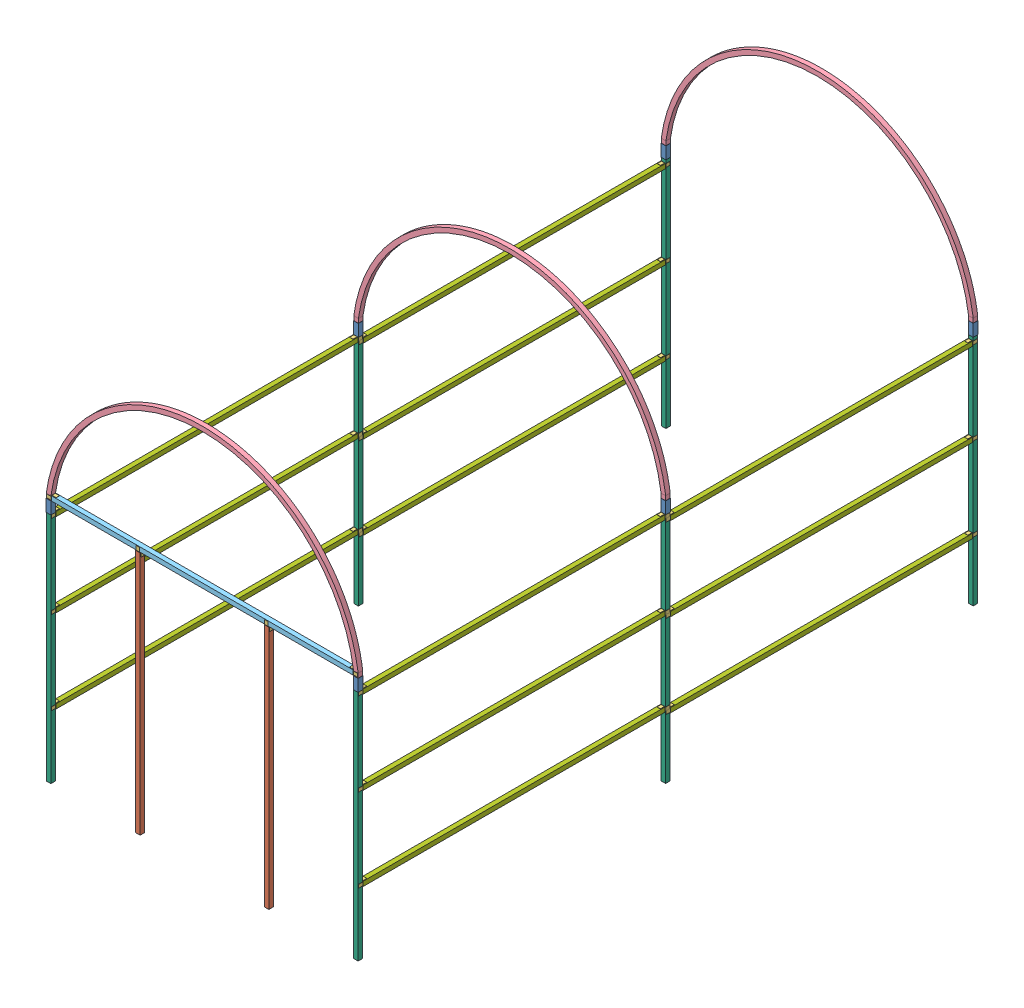
SolidWorks assembly SolarDryer_Frame, configuration Default. Lengths in mm.
Overall size (2062 2546.04 4095).
87 component instances, 8 part files, 49 mates.
Components (placement in the parent):
- Vertical joint-1: Vertical joint [Default] at (-1015 770.5 -2160.8996) size (32 80 32)
- VerticalBar-1: VerticalBar [Default] at (-425 0 -2160.8996) x (-1 0 0) z (0 0 1) size (30 1615 30)
- Wrapper-1: Wrapper [Default] at (-425 780.5 -2160.8996) x (0 0 -1) z (0 1 0) size (22 32 30)
- Arc_Bar-1: Arc_Bar [Default] at (0 838.5301 -2160.8996) x (0 0 -1) z (1 0 0) size (30.03 960.01 2060)
- LateralBar-1: LateralBar [Default] at (0 826.5 -2160.8996) x (0 0 -1) z (1 0 0) size (30 30 1992)
- Back_Wall-1: Back_Wall [Default] at (0 800 -2178.3996) size (2060 2500 5) (hidden)
- Wrapper-4: Wrapper [Default] at (-1027 826.5 -2160.8996) x (0 1 0) z (1 0 0) size (22 32 30)
- Wrapper-5: Wrapper [Default] at (-969 826.5 -2160.8996) x (0 0 1) z (-1 0 0) size (22 32 30)
- VerticalBar_Corners-1: VerticalBar_Corners [Default] at (-1015 -14.4849 -2160.8996) size (30 1586.03 30)
- Wrapper-8: Wrapper [Default] at (-425 838.5 -2160.8996) x (1 0 0) z (0 -1 0) size (22 32 30)
- VerticalBar-2: VerticalBar [Default] at (425 0 -2160.8996) x (1 0 0) z (0 0 -1) size (30 1615 30)
- Wrapper-9: Wrapper [Default] at (425 838.5 -2160.8996) x (1 0 0) z (0 -1 0) size (22 32 30)
- Wrapper-10: Wrapper [Default] at (425 780.5 -2160.8996) x (0 0 1) z (0 1 0) size (22 32 30)
- VerticalBar_Corners-2: VerticalBar_Corners [Default] at (1015 -14.4849 -2160.8996) x (-1 0 0) z (0 0 -1) size (30 1586.03 30)
- Vertical joint-2: Vertical joint [Default] at (1015 770.5 -2160.8996) x (-1 0 0) z (0 0 -1) size (32 80 32)
- Wrapper-11: Wrapper [Default] at (1027 826.5 -2160.8996) x (0 -1 0) z (-1 0 0) size (22 32 30)
- Wrapper-12: Wrapper [Default] at (969 826.5 -2160.8996) x (0 0 -1) z (1 0 0) size (22 32 30)
- VerticalBar_Corners-7: VerticalBar_Corners [Default] at (-1015 -14.4849 -4192.3996) size (30 1586.03 30)
- VerticalBar_Corners-8: VerticalBar_Corners [Default] at (-1015 -14.4849 -6223.8996) size (30 1586.03 30)
- Vertical joint-7: Vertical joint [Default] at (-1015 770.5 -4192.3996) size (32 80 32)
- Vertical joint-8: Vertical joint [Default] at (-1015 770.5 -6223.8996) size (32 80 32)
- VerticalBar_Corners-9: VerticalBar_Corners [Default] at (1015 -14.4849 -4192.3996) x (-1 0 0) z (0 0 -1) size (30 1586.03 30)
- VerticalBar_Corners-10: VerticalBar_Corners [Default] at (1015 -14.4849 -6223.8996) x (-1 0 0) z (0 0 -1) size (30 1586.03 30)
- Vertical joint-9: Vertical joint [Default] at (1015 770.5 -4192.3996) x (-1 0 0) z (0 0 -1) size (32 80 32)
- Vertical joint-10: Vertical joint [Default] at (1015 770.5 -6223.8996) x (-1 0 0) z (0 0 -1) size (32 80 32)
- Arc_Bar-4: Arc_Bar [Default] at (0 838.5301 -4192.3996) x (0 0 -1) z (1 0 0) size (30.03 960.01 2060)
- Arc_Bar-5: Arc_Bar [Default] at (0 838.5301 -6223.8996) x (0 0 -1) z (1 0 0) size (30.03 960.01 2060)
- Wrapper-13: Wrapper [Default] at (1015 719.5 -2148.8996) x (0 1 0) z (0 0 -1) size (22 32 30)
- Wrapper-15: Wrapper [Default] at (1015 717.5 -2206.8996) size (22 32 30)
- Wrapper-16: Wrapper [Default] at (1015 719.5 -4204.3996) x (0 -1 0) z (0 0 1) size (22 32 30)
- Wrapper-17: Wrapper [Default] at (1015 717.5 -4146.3996) x (-1 0 0) z (0 0 -1) size (22 32 30)
- HorizontalBarSides-1: HorizontalBarSides [Default] at (1015 717.5 -4174.3996) size (30 30 1995.5)
- Wrapper-22: Wrapper [Default] at (1015 697.5 -4180.3996) x (0 1 0) z (0 0 -1) size (22 32 30)
- Wrapper-23: Wrapper [Default] at (1015 695.5 -4238.3996) size (22 32 30)
- HorizontalBarSides-3: HorizontalBarSides [Default] at (1015 695.5 -6205.8996) size (30 30 1995.5)
- Wrapper-24: Wrapper [Default] at (1015 697.5 -6235.8996) x (0 -1 0) z (0 0 1) size (22 32 30)
- Wrapper-25: Wrapper [Default] at (1015 695.5 -6177.8996) x (-1 0 0) z (0 0 -1) size (22 32 30)
- Wrapper-26: Wrapper [Default] at (1015 147.5 -6235.8996) x (0 -1 0) z (0 0 1) size (22 32 30)
- Wrapper-27: Wrapper [Default] at (1015 -402.5 -6235.8996) x (0 -1 0) z (0 0 1) size (22 32 30)
- Wrapper-28: Wrapper [Default] at (1015 145.5 -6177.8996) x (-1 0 0) z (0 0 -1) size (22 32 30)
- Wrapper-29: Wrapper [Default] at (1015 -404.5 -6177.8996) x (-1 0 0) z (0 0 -1) size (22 32 30)
- HorizontalBarSides-4: HorizontalBarSides [Default] at (1015 145.5 -6205.8996) size (30 30 1995.5)
- HorizontalBarSides-5: HorizontalBarSides [Default] at (1015 -404.5 -6205.8996) size (30 30 1995.5)
- Wrapper-30: Wrapper [Default] at (1015 145.5 -4238.3996) size (22 32 30)
- Wrapper-31: Wrapper [Default] at (1015 -404.5 -4238.3996) size (22 32 30)
- Wrapper-32: Wrapper [Default] at (1015 147.5 -4180.3996) x (0 1 0) z (0 0 -1) size (22 32 30)
- Wrapper-33: Wrapper [Default] at (1015 -402.5 -4180.3996) x (0 1 0) z (0 0 -1) size (22 32 30)
- Wrapper-34: Wrapper [Default] at (1015 169.5 -4204.3996) x (0 -1 0) z (0 0 1) size (22 32 30)
- Wrapper-35: Wrapper [Default] at (1015 -380.5 -4204.3996) x (0 -1 0) z (0 0 1) size (22 32 30)
- Wrapper-36: Wrapper [Default] at (1015 167.5 -4146.3996) x (-1 0 0) z (0 0 -1) size (22 32 30)
- Wrapper-37: Wrapper [Default] at (1015 -382.5 -4146.3996) x (-1 0 0) z (0 0 -1) size (22 32 30)
- HorizontalBarSides-6: HorizontalBarSides [Default] at (1015 167.5 -4174.3996) size (30 30 1995.5)
- HorizontalBarSides-7: HorizontalBarSides [Default] at (1015 -382.5 -4174.3996) size (30 30 1995.5)
- Wrapper-38: Wrapper [Default] at (1015 169.5 -2148.8996) x (0 1 0) z (0 0 -1) size (22 32 30)
- Wrapper-39: Wrapper [Default] at (1015 -380.5 -2148.8996) x (0 1 0) z (0 0 -1) size (22 32 30)
- Wrapper-40: Wrapper [Default] at (1015 167.5 -2206.8996) size (22 32 30)
- Wrapper-41: Wrapper [Default] at (1015 -382.5 -2206.8996) size (22 32 30)
- Wrapper-42: Wrapper [Default] at (-1015 697.5 -6235.8996) x (0 1 0) z (0 0 1) size (22 32 30)
- Wrapper-43: Wrapper [Default] at (-1015 695.5 -6177.8996) x (-1 0 0) z (0 0 -1) size (22 32 30)
- HorizontalBarSides-8: HorizontalBarSides [Default] at (-1015 695.5 -4210.3996) x (-1 0 0) z (0 0 -1) size (30 30 1995.5)
- Wrapper-44: Wrapper [Default] at (-1015 695.5 -4238.3996) size (22 32 30)
- Wrapper-45: Wrapper [Default] at (-1015 697.5 -4180.3996) x (0 -1 0) z (0 0 -1) size (22 32 30)
- Wrapper-46: Wrapper [Default] at (-1015 719.5 -4204.3996) x (0 1 0) z (0 0 1) size (22 32 30)
- Wrapper-47: Wrapper [Default] at (-1015 717.5 -4146.3996) x (-1 0 0) z (0 0 -1) size (22 32 30)
- HorizontalBarSides-9: HorizontalBarSides [Default] at (-1015 717.5 -2178.8996) x (-1 0 0) z (0 0 -1) size (30 30 1995.5)
- Wrapper-48: Wrapper [Default] at (-1015 719.5 -2148.8996) x (0 -1 0) z (0 0 -1) size (22 32 30)
- Wrapper-49: Wrapper [Default] at (-1015 717.5 -2206.8996) size (22 32 30)
- Wrapper-50: Wrapper [Default] at (-1015 147.5 -6235.8996) x (0 1 0) z (0 0 1) size (22 32 30)
- Wrapper-51: Wrapper [Default] at (-1015 -402.5 -6235.8996) x (0 1 0) z (0 0 1) size (22 32 30)
- Wrapper-52: Wrapper [Default] at (-1015 145.5 -6177.8996) x (-1 0 0) z (0 0 -1) size (22 32 30)
- Wrapper-53: Wrapper [Default] at (-1015 -404.5 -6177.8996) x (-1 0 0) z (0 0 -1) size (22 32 30)
- HorizontalBarSides-10: HorizontalBarSides [Default] at (-1015 145.5 -4210.3996) x (-1 0 0) z (0 0 -1) size (30 30 1995.5)
- HorizontalBarSides-11: HorizontalBarSides [Default] at (-1015 -404.5 -4210.3996) x (-1 0 0) z (0 0 -1) size (30 30 1995.5)
- Wrapper-54: Wrapper [Default] at (-1015 145.5 -4238.3996) size (22 32 30)
- Wrapper-55: Wrapper [Default] at (-1015 -404.5 -4238.3996) size (22 32 30)
- Wrapper-56: Wrapper [Default] at (-1015 147.5 -4180.3996) x (0 -1 0) z (0 0 -1) size (22 32 30)
- Wrapper-57: Wrapper [Default] at (-1015 -402.5 -4180.3996) x (0 -1 0) z (0 0 -1) size (22 32 30)
- Wrapper-58: Wrapper [Default] at (-1015 169.5 -4204.3996) x (0 1 0) z (0 0 1) size (22 32 30)
- Wrapper-59: Wrapper [Default] at (-1015 -380.5 -4204.3996) x (0 1 0) z (0 0 1) size (22 32 30)
- Wrapper-60: Wrapper [Default] at (-1015 167.5 -4146.3996) x (-1 0 0) z (0 0 -1) size (22 32 30)
- Wrapper-61: Wrapper [Default] at (-1015 -382.5 -4146.3996) x (-1 0 0) z (0 0 -1) size (22 32 30)
- HorizontalBarSides-12: HorizontalBarSides [Default] at (-1015 167.5 -2178.8996) x (-1 0 0) z (0 0 -1) size (30 30 1995.5)
- HorizontalBarSides-13: HorizontalBarSides [Default] at (-1015 -382.5 -2178.8996) x (-1 0 0) z (0 0 -1) size (30 30 1995.5)
- Wrapper-62: Wrapper [Default] at (-1015 169.5 -2148.8996) x (0 -1 0) z (0 0 -1) size (22 32 30)
- Wrapper-63: Wrapper [Default] at (-1015 -380.5 -2148.8996) x (0 -1 0) z (0 0 -1) size (22 32 30)
- Wrapper-64: Wrapper [Default] at (-1015 167.5 -2206.8996) size (22 32 30)
- Wrapper-65: Wrapper [Default] at (-1015 -382.5 -2206.8996) size (22 32 30)
Mates (geometry in assembly coordinates):
- Coincident1: coincident anti-aligned: plane of Back_Wall-1 through (1030 0 -2175.8996) normal (0 -1 0)
- Coincident6: coincident anti-aligned: plane of LateralBar-1 through (996 811.5 -2175.8996) normal (0 0 -1); plane of Back_Wall-1 through (0 1460.6111 -2175.8996) normal (0 0 1)
- Coincident12: coincident aligned: plane of Back_Wall-1 through (0 800 -2178.3996) normal (1 0 0)
- Coincident15: coincident anti-aligned: plane of LateralBar-1 through (996 841.5 -2145.8996) normal (0 1 0); plane of Wrapper-5 through (-996 841.5 -2171.8996) normal (0 -1 0)
- Coincident16: coincident anti-aligned: plane of LateralBar-1 through (996 811.5 -2145.8996) normal (0 -1 0); plane of Wrapper-5 through (-969 811.5 -2171.8996) normal (0 1 0)
- Parallel4: parallel aligned: plane of LateralBar-1 through (996 811.5 -2175.8996) normal (0 0 -1); plane of Wrapper-5 through (-996 842.5 -2171.8996) normal (0 0 -1)
- Coincident19: coincident anti-aligned: plane of LateralBar-1 through (0 826.5 -2160.8996) normal (0 0 -1); plane of Wrapper-5 through (-969 826.5 -2160.8996) normal (0 0 1)
- Coincident23: coincident anti-aligned: plane of Wrapper-4 through (-998 815.5 -2173.8996) normal (-1 0 0); plane of Wrapper-5 through (-998 813.5 -2171.8996) normal (1 0 0)
- Coincident25: coincident aligned: plane of Wrapper-4 through (-1027 826.5 -2160.8996) normal (0 1 0); plane of Wrapper-5 through (-969 826.5 -2160.8996) normal (0 1 0)
- Coincident26: coincident aligned: plane of Arc_Bar-1; plane of LateralBar-1 through (0 826.5 -2160.8996) normal (1 0 0)
- Coincident27: coincident aligned: plane of Arc_Bar-1; plane of LateralBar-1 through (0 826.5 -2160.8996) normal (1 0 0)
- Parallel5: parallel anti-aligned: line of Arc_Bar-1 through (-1000 837.5 -2145.8996) axis (0 0 -1); line of LateralBar-1 through (-996 841.5 -2175.8996) axis (0 0 1)
- Coincident31: coincident: point of Arc_Bar-1; point of Wrapper-4
- Coincident32: coincident anti-aligned: plane of Vertical joint-1 through (-1000 810.5 -2175.8996) normal (0 0 1); plane of Arc_Bar-1 through (0 778.5301 -2175.8996) normal (0 0 -1)
- Coincident33: coincident anti-aligned: plane of Vertical joint-1 through (-1030 810.5 -2175.8996) normal (1 0 0); plane of Arc_Bar-1 through (-1030 778.5301 -2160.8996) normal (-1 0 0)
- Coincident34: coincident anti-aligned: plane of Wrapper-4 through (-998 815.5 -2173.8996) normal (-1 0 0); plane of Wrapper-5 through (-998 813.5 -2171.8996) normal (1 0 0)
- Coincident35: coincident aligned: plane of Wrapper-4 through (-1027 826.5 -2160.8996) normal (0 0 1); plane of Wrapper-5 through (-969 826.5 -2160.8996) normal (0 0 1)
- Coincident36: coincident anti-aligned: plane of Vertical joint-1 through (-1015 810.5 -2160.8996) normal (0 1 0); plane of Wrapper-5 through (-969 810.5 -2171.8996) normal (0 -1 0)
- Coincident42: coincident anti-aligned: line of VerticalBar-1 through (-410 807.5 -2175.8996) axis (0 0 1); line of Wrapper-1 through (-410 807.5 -2149.8996) axis (0 0 -1)
- Coincident43: coincident aligned: line of VerticalBar-1 through (-440 807.5 -2145.8996) axis (0 0 -1); line of Wrapper-1 through (-440 807.5 -2149.8996) axis (0 0 -1)
- Coincident44: coincident anti-aligned: plane of VerticalBar-1 through (-425 0 -2160.8996) normal (0 0 1); plane of Wrapper-1 through (-425 780.5 -2160.8996) normal (0 0 -1)
- Coincident45: coincident anti-aligned: plane of VerticalBar-1 through (-425 0 -2160.8996) normal (0 0 1); plane of LateralBar-1 through (0 826.5 -2160.8996) normal (0 0 -1)
- Parallel6: parallel anti-aligned: plane of VerticalBar-1 through (-425 0 -2160.8996) normal (-1 0 0); plane of LateralBar-1 through (0 826.5 -2160.8996) normal (1 0 0)
- Distance3: distance = 425 mm anti-aligned: plane of VerticalBar-1 through (-425 0 -2160.8996) normal (-1 0 0); plane of LateralBar-1 through (0 826.5 -2160.8996) normal (1 0 0)
- Coincident48: coincident anti-aligned: plane of Wrapper-1 through (-412 809.5 -2149.8996) normal (0 -1 0); plane of Wrapper-8 through (-436 809.5 -2173.8996) normal (0 1 0)
- Coincident49: coincident anti-aligned: plane of Wrapper-1 through (-425 780.5 -2160.8996) normal (-1 0 0); plane of Wrapper-8 through (-425 838.5 -2160.8996) normal (1 0 0)
- Coincident50: coincident anti-aligned: plane of Wrapper-1 through (-425 780.5 -2160.8996) normal (0 0 -1); plane of Wrapper-8 through (-425 838.5 -2160.8996) normal (0 0 1)
- Coincident51: coincident anti-aligned: line of LateralBar-1 through (996 811.5 -2145.8996) axis (-1 0 0); line of Wrapper-8 through (-436 811.5 -2145.8996) axis (1 0 0)
- Coincident52: coincident anti-aligned: plane of Arc_Bar-1 through (0 778.5301 -2160.8996) normal (0 -1 0); plane of VerticalBar_Corners-1 through (-1015 778.5301 -2160.8996) normal (0 1 0)
- Coincident53: coincident anti-aligned: plane of Vertical joint-1 through (-1000 810.5 -2175.8996) normal (0 0 1); plane of VerticalBar_Corners-1 through (-1030 778.5301 -2175.8996) normal (0 0 -1)
- Coincident54: coincident anti-aligned: plane of Vertical joint-1 through (-1000 810.5 -2175.8996) normal (-1 0 0); plane of VerticalBar_Corners-1 through (-1000 778.5301 -2175.8996) normal (1 0 0)
- Coincident57: coincident anti-aligned: plane of VerticalBar-1 through (-425 0 -2160.8996) normal (0 -1 0)
- Coincident58: coincident anti-aligned: line of VerticalBar_Corners-2 through (1000 778.5301 -2175.8996) axis (0 -1 0); line of Wrapper-13 through (1000 708.5 -2175.8996) axis (0 1 0)
- Coincident59: coincident anti-aligned: line of VerticalBar_Corners-2 through (1030 778.5301 -2175.8996) axis (0 -1 0); line of Wrapper-13 through (1030 708.5 -2175.8996) axis (0 1 0)
- Coincident60: coincident aligned: plane of Wrapper-13 through (1015 719.5 -2148.8996) normal (1 0 0); plane of Wrapper-15 through (1015 717.5 -2206.8996) normal (1 0 0)
- Coincident61: coincident aligned: plane of Wrapper-13 through (1015 719.5 -2148.8996) normal (1 0 0); plane of Wrapper-15 through (1015 717.5 -2206.8996) normal (1 0 0)
- Coincident63: coincident anti-aligned: plane of Wrapper-13 through (1002 708.5 -2177.8996) normal (0 0 1); plane of Wrapper-15 through (1004 704.5 -2177.8996) normal (0 0 -1)
- Coincident64: coincident anti-aligned: plane of Vertical joint-2 through (1015 730.5 -2160.8996) normal (0 -1 0); plane of Wrapper-13 through (1031 730.5 -2175.8996) normal (0 1 0)
- Coincident65: coincident aligned: line of Wrapper-13 through (1002 730.5 -2177.8996) axis (1 0 0); line of Wrapper-15 through (1004 730.5 -2177.8996) axis (1 0 0)
- Coincident67: coincident aligned: line of VerticalBar_Corners-9 through (1000 778.5301 -4177.3996) axis (0 -1 0); line of Wrapper-16 through (1000 730.5 -4177.3996) axis (0 -1 0)
- Coincident68: coincident aligned: unknown of Arc_Bar-1
- Coincident69: coincident aligned: line of VerticalBar_Corners-9 through (1030 778.5301 -4177.3996) axis (0 -1 0); line of Wrapper-16 through (1030 730.5 -4177.3996) axis (0 -1 0)
- Coincident70: coincident anti-aligned: plane of Vertical joint-9 through (1015 730.5 -4192.3996) normal (0 -1 0); plane of Wrapper-16 through (1031 730.5 -4177.3996) normal (0 1 0)
- Coincident71: coincident anti-aligned: plane of Wrapper-16 through (1002 730.5 -4175.3996) normal (0 0 -1); plane of Wrapper-17 through (1026 704.5 -4175.3996) normal (0 0 1)
- Coincident72: coincident anti-aligned: line of Wrapper-16 through (1002 730.5 -4175.3996) axis (1 0 0); line of Wrapper-17 through (1026 730.5 -4175.3996) axis (-1 0 0)
- Coincident73: coincident anti-aligned: plane of Wrapper-16 through (1015 719.5 -4204.3996) normal (1 0 0); plane of Wrapper-17 through (1015 717.5 -4146.3996) normal (-1 0 0)
- Coincident74: coincident anti-aligned: plane of Wrapper-16 through (1002 730.5 -4174.3996) normal (0 0 1); plane of HorizontalBarSides-1 through (1015 717.5 -4174.3996) normal (0 0 -1)
- Coincident75: coincident anti-aligned: plane of Wrapper-17 through (1015 717.5 -4146.3996) normal (-1 0 0); plane of HorizontalBarSides-1 through (1015 717.5 -4174.3996) normal (1 0 0)
- Coincident76: coincident anti-aligned: plane of Wrapper-15 through (1004 732.5 -2179.8996) normal (0 -1 0); plane of HorizontalBarSides-1 through (1030 732.5 -2178.8996) normal (0 1 0)
